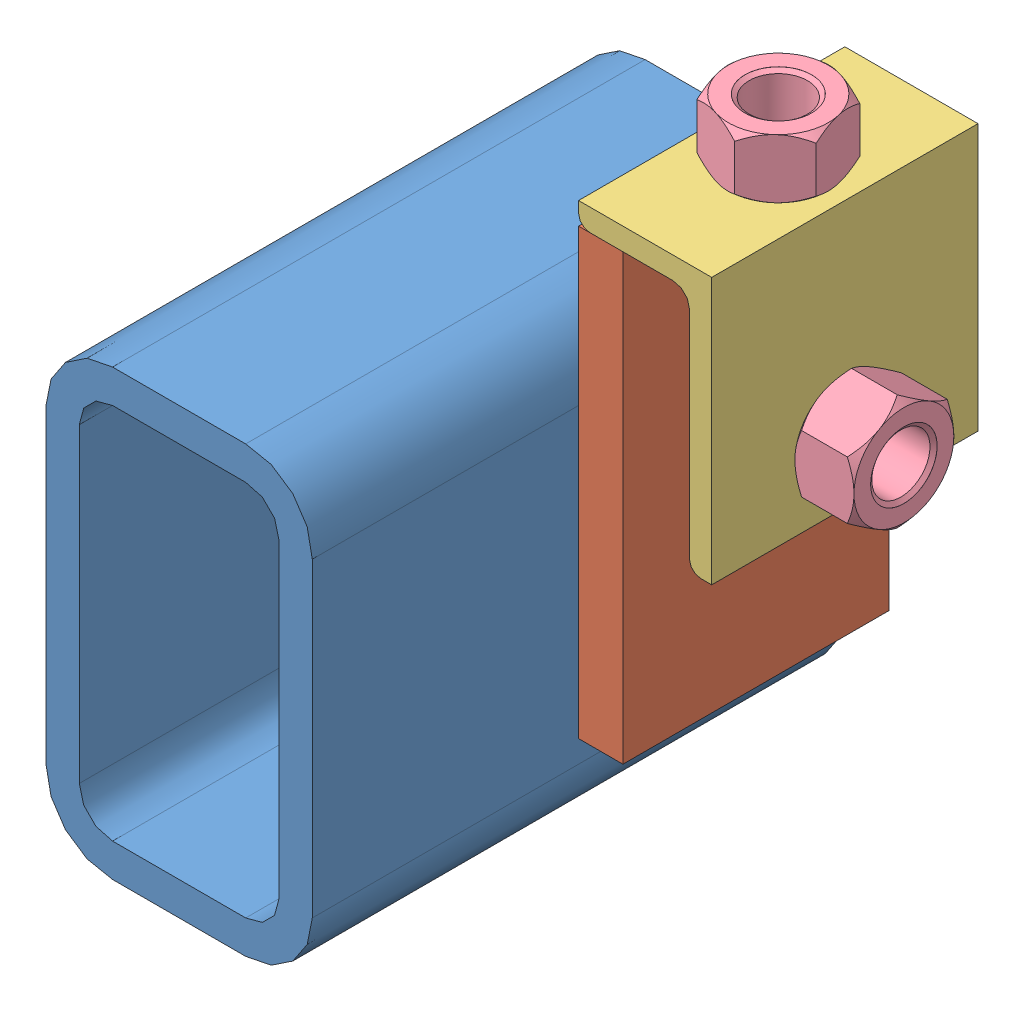
SolidWorks assembly drawer support ass, configuration Default. Lengths in mm.
Overall size (131.19 175.64 152.4).
5 component instances, 4 part files, 11 mates.
Components (placement in the parent):
- tube rectangular_Drawer support-1: tube rectangular_Drawer support [PreviewCfg] at (-125.0223 -60.8485 44.0663) size (76.2 127 152.4)
- drawer support member-1: drawer support member [Default] at (-36.1223 -35.4485 -32.1337) x (0 1 0) z (0 0 1) size (127 12.7 76.2)
- drawer support angle-1: drawer support angle [PreviewCfg] at (-10.7223 97.9015 5.9663) x (-1 0 0) z (0 0 1) size (38.1 76.2 76.2)
- hex nut_ai-2: hex nut_ai [HNUT 0.7500-10-D-C] at (-10.7223 40.7515 5.9663) x (0 0 1) z (-1 0 0) size (28.57 33 16.89)
- hex nut_ai-5: hex nut_ai [HNUT 0.7500-10-D-C] at (-29.7723 97.9015 5.9663) x (0.29785 0 -0.954613) z (0 -1 0) size (28.57 33 16.89)
Mates (geometry in assembly coordinates):
- Coincident1: coincident anti-aligned: plane of tube rectangular_Drawer support-1 through (-48.8223 47.1015 120.2663) normal (1 0 0); plane of drawer support member-1 through (-48.8223 -35.4485 -32.1337) normal (-1 0 0)
- Distance1: distance = 25.4 mm aligned: plane of drawer support member-1 through (-48.8223 -35.4485 -32.1337) normal (0 -1 0); plane of tube rectangular_Drawer support-1 through (-105.9723 -60.8485 120.2663) normal (0 -1 0)
- Coincident4: coincident anti-aligned: plane of drawer support member-1 through (-48.8223 91.5515 -32.1337) normal (0 1 0); plane of drawer support angle-1 through (-21.8348 91.5515 44.0663) normal (0 -1 0)
- Coincident5: coincident aligned: plane of drawer support member-1 through (-48.8223 -35.4485 44.0663) normal (0 0 1); plane of drawer support angle-1 through (-13.9024 24.8715 44.0663) normal (0 0 1)
- Coincident6: coincident aligned: plane of drawer support member-1 through (-48.8223 -35.4485 -32.1337) normal (-1 0 0); plane of drawer support angle-1 through (-48.8223 94.7215 44.0663) normal (-1 0 0)
- Concentric1: concentric: cylinder of drawer support angle-1 through (-29.7723 21.7005 101.2163) axis (0 1 0) radius 6.35; cylinder of hex nut_ai-5 through (-29.7723 135.5923 101.2163) axis (0 -1 0) radius 8.3337
- Concentric4: concentric anti-aligned: cylinder of drawer support angle-1 through (-48.8223 40.7515 5.9663) axis (1 0 0) radius 6.35; cylinder of hex nut_ai-2 through (6.1687 40.7515 5.9663) axis (-1 0 0) radius 8.3337
- Coincident7: coincident anti-aligned: plane of drawer support angle-1 through (-10.7223 97.9015 44.0663) normal (1 0 0); plane of hex nut_ai-2 through (-10.7223 57.2493 5.9663) normal (-1 0 0)
- Coincident8: coincident anti-aligned: plane of drawer support angle-1 through (-48.8223 97.9015 44.0663) normal (0 1 0); plane of hex nut_ai-5 through (-14.0233 97.9015 10.8802) normal (0 -1 0)
- Coincident10: coincident aligned: plane of tube rectangular_Drawer support-1 through (-67.8723 47.1015 -32.1337) normal (0 0 -1); plane of drawer support member-1 through (-48.8223 -35.4485 -32.1337) normal (0 0 -1)
- Concentric5: concentric anti-aligned: cylinder of drawer support angle-1 through (-29.7723 21.7005 5.9663) axis (0 1 0) radius 6.35; cylinder of hex nut_ai-5 through (-29.7723 114.7925 5.9663) axis (0 -1 0) radius 8.3337
